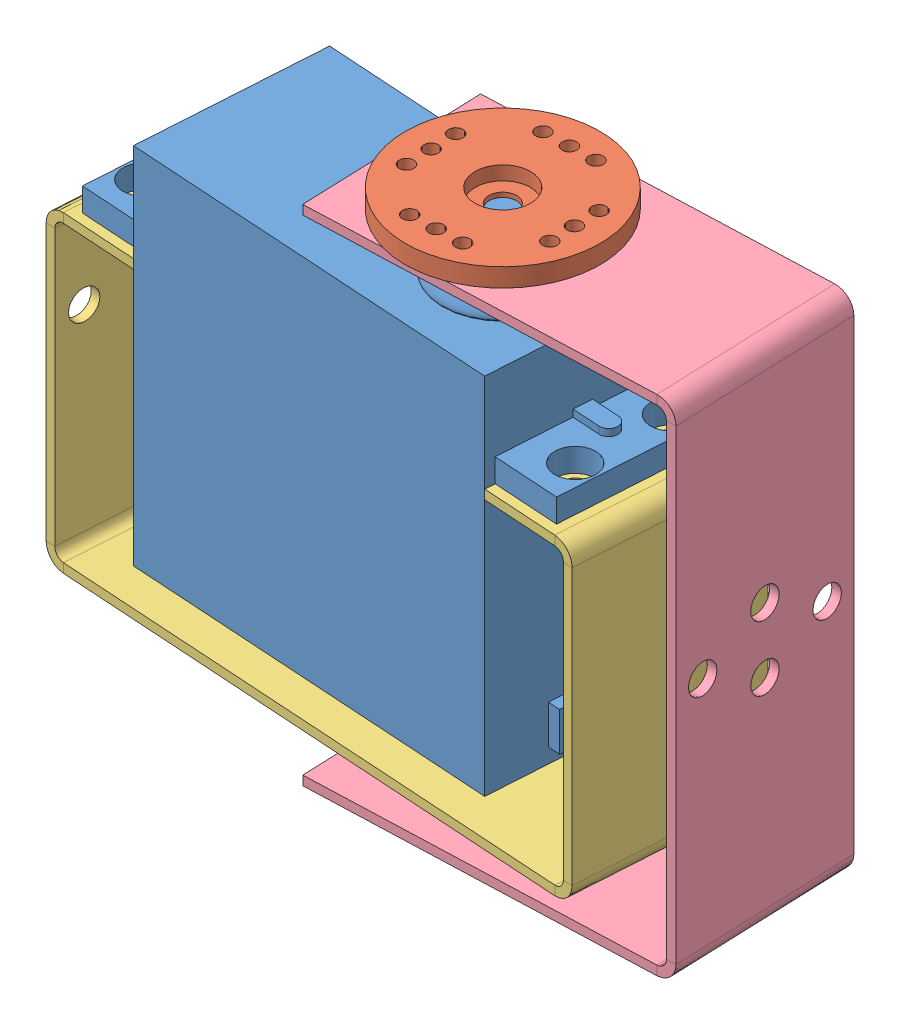
SolidWorks assembly servo_motor_bracket3, configuration ﾃﾞﾌｫﾙﾄ. Lengths in mm.
Overall size (69.84 56.5 23.85).
5 component instances, 5 part files, 8 mates.
Components (placement in the parent):
- servo_motor-1: servo_motor [ﾃﾞﾌｫﾙﾄ] at (-18.7499 -22.7875 62.9154) x (0.997965 0 0.063768) z (-0.063768 0 0.997965) size (54.94 45.5 20)
- servo_motor_soucer-1: servo_motor_soucer [ﾃﾞﾌｫﾙﾄ] at (13.2538 22.7125 54.94) x (0.999327 0 -0.036692) z (0.036692 0 0.999327) size (21.05 5.7 21.05)
- servo_bracket3_base-2: servo_bracket3_base [ﾃﾞﾌｫﾙﾄ] at (-28.8493 -27.7875 62.2701) x (0.997965 0 0.063768) z (-0.063768 0 0.997965) size (60.94 33.81 20)
- servo_bracket3_cover-1: servo_bracket3_cover [ﾃﾞﾌｫﾙﾄ] at (39.993 -31.7875 63.965) x (0.999327 0 -0.036692) z (0.036692 0 0.999327) size (39 54.5 20)
- M3_spacer-1: M3_spacer [ﾃﾞﾌｫﾙﾄ] at (13.2538 -30.7875 54.94) size (7 3 7)
Mates (geometry in assembly coordinates):
- 一致3: coincident anti-aligned: circle of servo_motor-1; circle of servo_motor_soucer-1
- 同心円3: concentric aligned: circle of servo_motor-1; circle of servo_bracket3_base-2
- 一致4: coincident anti-aligned: plane of servo_motor-1 through (29.0404 6.0225 64.907) normal (0 -1 0); plane of servo_bracket3_base-2 through (-28.8493 6.0225 62.2701) normal (0 1 0)
- 同心円4: concentric aligned: circle of servo_motor_soucer-1; circle of servo_bracket3_cover-1
- 同心円5: concentric aligned: circle of servo_motor_soucer-1; circle of servo_bracket3_cover-1
- 一致6: coincident anti-aligned: plane of servo_motor_soucer-1 through (13.2538 22.7125 54.94) normal (0 -1 0); plane of servo_bracket3_cover-1 through (40.9923 22.7125 63.9283) normal (0 1 0)
- 一致7: coincident anti-aligned: circle of servo_bracket3_base-2; circle of M3_spacer-1
- 同心円6: concentric aligned: circle of servo_motor-1; circle of servo_bracket3_base-2
